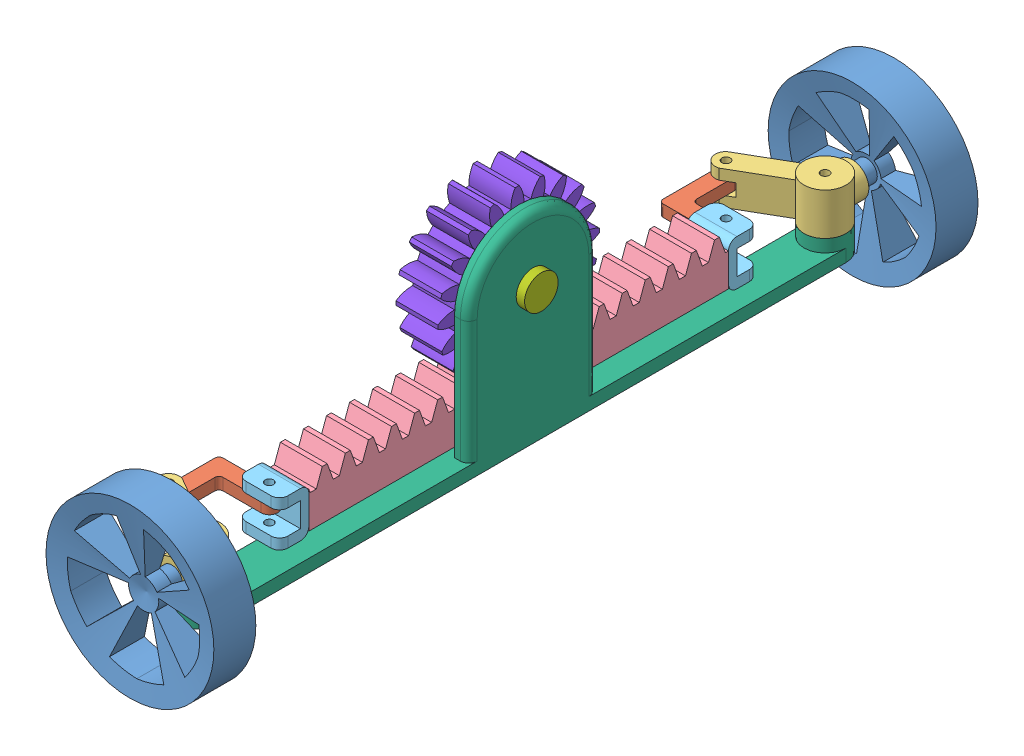
SolidWorks assembly Front mechanism, configuration Default. Lengths in mm.
Overall size (53.98 69.81 182.74).
16 component instances, 9 part files, 12 mates.
Components (placement in the parent):
- Wheel + connecting rod LH-1: Wheel + connecting rod LH [Default] at (55.4946 -17.5158 -113.1438) size (53.98 53.98 38.94)
  - Wheel-1: Wheel [Default] at (-52.7374 48.4431 145.7708) x (-0.886318 0.463077 0) z (0 0 1) size (40 40 15.31)
  - Connecting rod-2: Connecting rod [Default] at (-69.237 49.3849 166.634) x (1 0 0) z (0 -1 0) size (16 16 2.8)
  - Tie Rod-1: Tie Rod [Default] at (-52.7374 48.4431 152.7181) size (22.97 10 17.19)
- Wheel + connecting rod RH-1: Wheel + connecting rod RH [Default] at (142.0774 -20.3764 249.2732) x (0 0 1) z (-1 0 0) size (38.94 44.63 44.63)
  - Wheel-1: Wheel [Default] at (-40.6338 50.1873 139.2907) x (0 0.123444 -0.992352) z (-1 0 0) size (40 40 15.31)
  - Connecting rod-2: Connecting rod [Default] at (-75.2998 52.2455 141.9875) x (1 0 0) z (0 -1 0) size (16 16 2.8)
  - Tie Rod-1: Tie Rod [Default] at (-47.5811 50.1873 139.2907) x (0 0 -1) z (-1 0 0) size (22.97 10 17.19)
- Rack and Pinion-1: Rack and Pinion [Default] at (4.3622 48.3129 107.8659) x (0 0 1) z (-1 0 0) size (114 12.75 10)
  - rack spur rectangular_am-1: rack spur rectangular_am [Metric - Rack-spur - rectangular 1.75M 20PA 10FW 10PH 100L---SAll] at (-37.2327 -23.7568 10) size (100 11.75 10)
  - Extra rack part for connection-1: Extra rack part for connection [Default] at (62.7673 -17.8749 1.6667) x (0 0 -1) z (1 0 0) size (10 10.81 7)
  - Extra rack part for connection-2: Extra rack part for connection [Default] at (-37.2327 -17.8749 8.3333) x (0 0 1) z (-1 0 0) size (10 10.81 7)
- Fixed rod-1: Fixed rod [Default] at (-1.4451 19.3691 110.2257) x (0.000198 0 1) z (0 1 0) size (159.23 16.8 47.56)
- inprogress screw-1: inprogress screw [Default] at (7.772 51.6191 120.6327) x (0.000198 0 1) z (-1 0 0.000198) size (8 8 18.8)
- spur gear_am_edited-2: spur gear_am_edited [Metric - Spur gear 1.75M 20T 20PA 10FW ---S20N75H50L0.8N] at (-5.638 51.6191 120.6354) x (1 0 -0.000198) z (0.000035 0.98448 0.175497) size (10 38.16 38.16)
- screwholder-1: screwholder [Default] at (-6.028 51.6191 120.6354) x (0.000198 0 1) z (-1 0 0.000198) size (7 7 3)
Mates (geometry in assembly coordinates):
- Hinge1: hinge anti-aligned: cylinder of Wheel + connecting rod RH-1/Connecting rod-2 through (-0.623 29.0691 175.0632) axis (0 1 0) radius 1; cylinder of Rack and Pinion-1/Extra rack part for connection-1 through (-0.623 23.5561 175.0632) axis (0 1 0) radius 1; plane of Rack and Pinion-1/Extra rack part for connection-1 through (-5.6378 31.8691 177.6332) normal (0 -1 0); plane of Wheel + connecting rod RH-1/Connecting rod-2 through (-0.623 31.8691 175.0632) normal (0 1 0)
- Hinge2: hinge anti-aligned: cylinder of Wheel + connecting rod LH-1/Connecting rod-2 through (-0.6525 29.0691 66.2032) axis (0 1 0) radius 1; cylinder of Rack and Pinion-1/Extra rack part for connection-2 through (-0.6525 23.5561 66.2032) axis (0 1 0) radius 1; plane of Rack and Pinion-1/Extra rack part for connection-2 through (4.3622 31.8691 63.6332) normal (0 -1 0); plane of Wheel + connecting rod LH-1/Connecting rod-2 through (-12.6525 31.8691 54.2032) normal (0 1 0)
- Parallel1: parallel anti-aligned: line of Wheel + connecting rod LH-1/Connecting rod-2 through (-0.6525 31.8691 68.2032) axis (-1 0 0); line of Rack and Pinion-1/Extra rack part for connection-2 through (-3.6378 34.3691 63.6332) axis (1 0 0)
- Parallel2: parallel anti-aligned: line of Wheel + connecting rod RH-1/Connecting rod-2 through (-13.623 31.8691 173.0632) axis (1 0 0); line of Rack and Pinion-1/Extra rack part for connection-1 through (4.3622 34.3691 172.6332) axis (-1 0 0)
- Coincident6: coincident anti-aligned: circle of Wheel + connecting rod RH-1/Tie Rod-1; circle of Fixed rod-1
- Coincident7: coincident aligned: circle of Wheel + connecting rod LH-1/Tie Rod-1; circle of Fixed rod-1
- Concentric1: concentric aligned: cylinder of Fixed rod-1 through (4.362 51.6191 120.6334) axis (1 0 -0.000198) radius 2.5; cylinder of inprogress screw-1 through (-9.028 51.6191 120.636) axis (1 0 -0.000198) radius 2.375
- Coincident8: coincident anti-aligned: plane of Fixed rod-1 through (7.7572 22.3691 46.0177) normal (1 0 -0.000198); plane of inprogress screw-1 through (7.772 51.6191 120.6327) normal (-1 0 0.000198)
- Concentric2: concentric aligned: cylinder of inprogress screw-1 through (-9.028 51.6191 120.636) axis (1 0 -0.000198) radius 2.375; cylinder of spur gear_am_edited-2 through (-5.638 51.6191 120.6354) axis (1 0 -0.000198) radius 2.5
- Coincident9: coincident anti-aligned: plane of Fixed rod-1 through (4.362 51.6191 120.6334) normal (-1 0 0.000198); plane of spur gear_am_edited-2 through (4.362 51.6191 120.6334) normal (1 0 -0.000198)
- Concentric3: concentric aligned: cylinder of inprogress screw-1 through (-9.028 51.6191 120.636) axis (1 0 -0.000198) radius 2.375; cylinder of screwholder-1 through (-9.028 51.6191 120.636) axis (1 0 -0.000198) radius 2.375
- Coincident10: coincident aligned: plane of inprogress screw-1 through (-9.028 51.6191 120.636) normal (-1 0 0.000198); plane of screwholder-1 through (-9.028 51.6191 120.636) normal (-1 0 0.000198)
